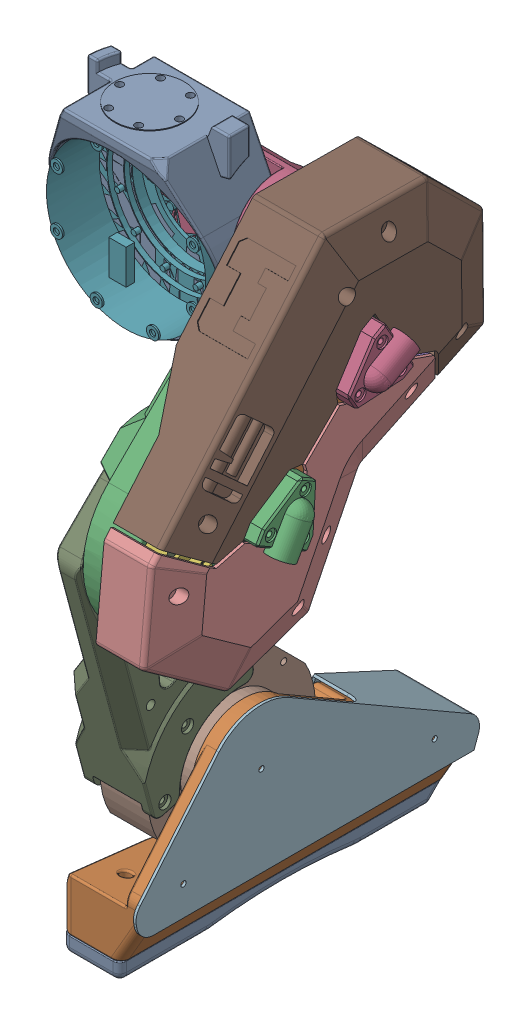
SolidWorks assembly 右腿, configuration 默认. Lengths in mm.
Overall size (184.93 459.26 275.12).
15 component instances, 12 part files, 44 mates.
Components (placement in the parent):
- 大腿right_yaw-1: 大腿right_yaw [默认] at (0 -55.5 53) size (99.54 110 58)
- 脚掌right_pitch-1: 脚掌right_pitch [默认] at (83.2 -422.4881 168.8962) x (0 -0.619688 -0.784849) z (-1 0 0) size (169.64 143.55 45)
- 大腿right_pitch-1: 大腿right_pitch [默认] at (63 -62.5711 79.7817) x (0 -0.707107 0.707107) z (-1 0 0) size (220 100.08 52.07)
- 大腿right_roll-1: 大腿right_roll [默认] at (63 -55.5 2) x (0 0 -1) z (1 0 0) size (71.94 70 103.87)
- A1电机模型-1: A1电机模型 [默认] at (107.05 -55.5 2) x (0 0.5 -0.866025) z (-1 0 0) size (92 92 49.05)
- A1电机模型-2: A1电机模型 [默认] at (107.05 -140.3528 86.8528) x (0 -0.866025 0.5) z (-1 0 0) size (92 92 49.05)
- A1电机模型-3: A1电机模型 [默认] at (0 -55.5 44.05) x (0 -1 0) z (0 0 -1) size (92 92 49.05)
- Go2电机模型-1: Go2电机模型 [默认] at (39.8 -275.5824 50.6181) x (0 0.707107 -0.707107) z (1 0 0) size (92.5 96.5 42.4)
- 小腿right_pitch-1: 小腿right_pitch [默认] at (73.5 -140.3528 86.8528) x (0 0.707107 -0.707107) z (1 0 0) size (144.22 133.76 40.34)
- 右大腿外壳-1: 右大腿外壳 [默认] at (70.05 -125.3028 488.7467) x (0 0.087156 -0.996195) z (1 0 0) size (207.48 194.95 50)
- 右脚鞋面壳-1: 右脚鞋面壳 [默认] at (83.2 -83.9006 -112.4365) x (0 0 -1) z (1 0 0) size (198.24 84 49)
- 鞋底脚板-1: 鞋底脚板 [默认] at (38.4265 -40.6299 -49.2728) x (0 -0.691677 -0.722207) z (1 0 0) size (136.26 135.6 33)
- 大腿左穿线板2-1: 大腿左穿线板2 [默认] at (108 -76.8035 65.5494) x (0 0.707107 -0.707107) z (1 0 0) size (105.13 45.22 9)
- 大腿波纹管连接件-2: 大腿波纹管连接件 [默认] at (117 -129.9252 80.9139) x (0 0.866025 -0.5) z (1 0 0) size (35 34 17.5)
- 大腿波纹管连接件-3: 大腿波纹管连接件 [默认] at (117 -61.4389 12.4276) x (0 -0.5 0.866025) z (1 0 0) size (35 34 17.5)
Mates (geometry in assembly coordinates):
- 重合1: coincident anti-aligned: plane of 大腿right_yaw-1 through (0 -55.5 10.5) normal (0 0 1); plane of A1电机模型-3 through (0 -55.5 10.5) normal (0 0 -1)
- 同心1: concentric aligned: cylinder of 大腿right_yaw-1 through (0 -55.5 0) axis (0 0 1) radius 46.5; cylinder of A1电机模型-3 through (0 -55.5 13.5) axis (0 0 1) radius 46
- 重合2: coincident aligned: plane of 大腿right_yaw-1 through (-5.5 0 25) normal (0 1 0)
- 重合3: coincident anti-aligned: plane of A1电机模型-3 through (0 -55.5 0) normal (0 0 -1)
- 对称1: symmetric aligned: plane of A1电机模型-3 through (-5 -55.5 49.05) normal (-1 0 0); plane of A1电机模型-3 through (5 -55.5 49.05) normal (1 0 0)
- 重合4: coincident anti-aligned: plane of 大腿right_roll-1 through (0 -55.5 0) normal (0 0 1); plane of A1电机模型-3 through (0 -55.5 0) normal (0 0 -1)
- 同心2: concentric: cylinder of 大腿right_yaw-1 through (0 -55.5 0) axis (0 0 1) radius 49; sphere of 大腿right_roll-1
- 同心3: concentric anti-aligned: cylinder of 大腿right_pitch-1 through (108 -55.5 2) axis (-1 0 0) radius 50; cylinder of A1电机模型-1 through (76.5 -55.5 2) axis (1 0 0) radius 46
- 重合5: coincident anti-aligned: plane of 大腿right_pitch-1 through (73.5 -55.5 2) normal (1 0 0); plane of A1电机模型-1 through (73.5 -55.5 2) normal (-1 0 0)
- 重合6: coincident aligned: plane of A1电机模型-1 through (63 -55.5 2) normal (-1 0 0); plane of A1电机模型-2 through (63 -140.3528 86.8528) normal (-1 0 0)
- 同心4: concentric anti-aligned: cylinder of 大腿right_pitch-1 through (108 -140.3528 86.8528) axis (-1 0 0) radius 50; cylinder of A1电机模型-2 through (76.5 -140.3528 86.8528) axis (1 0 0) radius 46
- 重合7: coincident anti-aligned: plane of A1电机模型-2 through (63 -140.3528 86.8528) normal (-1 0 0); plane of 小腿right_pitch-1 through (63 -140.3528 86.8528) normal (1 0 0)
- 同心5: concentric anti-aligned: cylinder of 大腿right_pitch-1 through (108 -140.3528 86.8528) axis (-1 0 0) radius 50; cylinder of 小腿right_pitch-1 through (33.5 -140.3528 86.8528) axis (1 0 0) radius 35
- 重合8: coincident anti-aligned: plane of 大腿right_roll-1 through (63 -55.5 2) normal (1 0 0); plane of A1电机模型-1 through (63 -55.5 2) normal (-1 0 0)
- 同心6: concentric anti-aligned: cylinder of 大腿right_pitch-1 through (108 -55.5 2) axis (-1 0 0) radius 50; cylinder of 大腿right_roll-1 through (62 -55.5 2) axis (1 0 0) radius 28
- 重合9: coincident anti-aligned: plane of Go2电机模型-1 through (67.5 -275.5824 50.6181) normal (1 0 0); plane of 小腿right_pitch-1 through (67.5 -275.5824 50.6181) normal (-1 0 0)
- 同心7: concentric anti-aligned: cylinder of Go2电机模型-1 through (67.5 -275.5824 50.6181) axis (-1 0 0) radius 48.25; cylinder of 小腿right_pitch-1 through (39.8 -275.5824 50.6181) axis (1 0 0) radius 50.5
- 同心8: concentric aligned: cylinder of Go2电机模型-1 through (44.8 -233.0824 50.6181) axis (-1 0 0) radius 1.75; cylinder of 小腿right_pitch-1 through (43.5 -233.0824 50.6181) axis (-1 0 0) radius 1.75
- 重合10: coincident anti-aligned: plane of 脚掌right_pitch-1 through (74.2 -422.4881 -89.4581) normal (-1 0 0); plane of Go2电机模型-1 through (74.2 -275.5824 50.6181) normal (1 0 0)
- 同心9: concentric anti-aligned: cylinder of 脚掌right_pitch-1 through (38.2 -275.5824 50.6181) axis (1 0 0) radius 30; cylinder of Go2电机模型-1 through (74.2 -275.5824 50.6181) axis (-1 0 0) radius 29.5
- 重合11: coincident anti-aligned: plane of 脚掌right_pitch-1 through (83.2 -422.4881 168.8962) normal (1 0 0); plane of 右脚鞋面壳-1 through (83.2 -275.5824 50.6181) normal (-1 0 0)
- 同心10: concentric aligned: cylinder of 脚掌right_pitch-1 through (38.2 -275.5824 50.6181) axis (1 0 0) radius 30; cylinder of 右脚鞋面壳-1 through (37.2 -275.5824 50.6181) axis (1 0 0) radius 32
- 同心11: concentric aligned: cylinder of 脚掌right_pitch-1 through (78.2 -310.5824 -49.3819) axis (1 0 0) radius 2.5; cylinder of 右脚鞋面壳-1 through (82.7 -310.5824 -49.3819) axis (1 0 0) radius 1.5
- 重合12: coincident anti-aligned: plane of 脚掌right_pitch-1 through (71.653 -345.5824 -89.4581) normal (0 -1 0); plane of 鞋底脚板-1 through (71.4265 -345.5824 119.1489) normal (0 1 0)
- 同心12: concentric aligned: cylinder of 脚掌right_pitch-1 through (54.9265 -285.5824 -38.8511) axis (0 -1 0) radius 1.55; cylinder of 鞋底脚板-1 through (54.9265 -251.1705 -38.8511) axis (0 -1 0) radius 1.55
- 同心13: concentric aligned: cylinder of 脚掌right_pitch-1 through (54.9265 -285.5824 99.1489) axis (0 -1 0) radius 1.55; cylinder of 鞋底脚板-1 through (54.9265 -251.1705 99.1489) axis (0 -1 0) radius 1.55
- 重合13: coincident anti-aligned: plane of 大腿right_pitch-1 through (108 -55.5 2) normal (1 0 0); plane of 大腿左穿线板2-1 through (108 -76.8035 65.5494) normal (-1 0 0)
- 同心14: concentric aligned: cylinder of A1电机模型-1 through (108.05 -61.0474 44.1364) axis (-1 0 0) radius 1.75; cylinder of 大腿左穿线板2-1 through (117 -61.0474 44.1364) axis (-1 0 0) radius 1.75
- 同心15: concentric aligned: cylinder of A1电机模型-1 through (108.05 -89.2175 27.8724) axis (-1 0 0) radius 1.75; cylinder of 大腿左穿线板2-1 through (117 -89.2175 27.8724) axis (-1 0 0) radius 1.75
- 同心17: concentric aligned: cylinder of A1电机模型-2 through (108.05 -114.4805 53.1353) axis (-1 0 0) radius 1.75; cylinder of 大腿左穿线板2-1 through (117 -114.4805 53.1353) axis (-1 0 0) radius 1.75
- 同心18: concentric aligned: cylinder of A1电机模型-2 through (108.05 -98.2164 81.3055) axis (-1 0 0) radius 1.75; cylinder of 大腿左穿线板2-1 through (117 -98.2164 81.3055) axis (-1 0 0) radius 1.75
- 重合14: coincident anti-aligned: plane of A1电机模型-2 through (108.05 -145.9002 44.7164) normal (1 0 0); plane of 右大腿外壳-1 through (108.05 -29.6276 35.7175) normal (-1 0 0)
- 同心19: concentric aligned: cylinder of A1电机模型-1 through (108.05 -13.3636 7.5474) axis (-1 0 0) radius 1.75; cylinder of 右大腿外壳-1 through (110.05 -13.3636 7.5474) axis (-1 0 0) radius 1.75
- 同心20: concentric aligned: cylinder of A1电机模型-1 through (108.05 -81.3724 -31.7175) axis (-1 0 0) radius 1.75; cylinder of 右大腿外壳-1 through (110.05 -81.3724 -31.7175) axis (-1 0 0) radius 1.75
- 同心21: concentric aligned: cylinder of 大腿左穿线板2-1 through (117 -74.9389 35.8103) axis (-1 0 0) radius 1.5; cylinder of 大腿波纹管连接件-3 through (127 -74.9389 35.8103) axis (-1 0 0) radius 1.5
- 重合15: coincident anti-aligned: plane of 大腿左穿线板2-1 through (117 -76.8035 65.5494) normal (1 0 0); plane of 大腿波纹管连接件-3 through (117 -61.4389 12.4276) normal (-1 0 0)
- 同心22: concentric aligned: cylinder of 大腿左穿线板2-1 through (117 -54.9126 23.1237) axis (-1 0 0) radius 1.5; cylinder of 大腿波纹管连接件-3 through (127 -54.9126 23.1237) axis (-1 0 0) radius 1.5
- 重合16: coincident aligned: plane of 大腿波纹管连接件-2 through (127 -129.9252 80.9139) normal (1 0 0); plane of 大腿波纹管连接件-3 through (127 -61.4389 12.4276) normal (1 0 0)
- 同心23: concentric aligned: cylinder of 大腿左穿线板2-1 through (117 -106.5425 67.4139) axis (-1 0 0) radius 1.5; cylinder of 大腿波纹管连接件-2 through (127 -106.5425 67.4139) axis (-1 0 0) radius 1.5
- 同心24: concentric aligned: cylinder of 大腿左穿线板2-1 through (117 -119.2291 87.4402) axis (-1 0 0) radius 1.5; cylinder of 大腿波纹管连接件-2 through (127 -119.2291 87.4402) axis (-1 0 0) radius 1.5
- 平行2: parallel: plane of 大腿right_yaw-1 through (-5.5 0 25) normal (0 1 0); line of 大腿right_roll-1 through (57.5 -21.2669 -5.0854) axis (-1 0 0)
- 平行3: parallel anti-aligned: plane of 大腿right_yaw-1 through (-5.5 0 25) normal (0 1 0); plane of 鞋底脚板-1 through (71.4265 -355.5824 -69.8511) normal (0 -1 0)
- 角度1: planar angle = 0.523599 rad anti-aligned: plane of 大腿right_roll-1 through (52 -50.5 34.1131) normal (0 1 0); plane of 大腿right_pitch-1 through (59 -19.2572 54.7744) normal (0 -0.866025 0.5)
- 角度2: planar angle = 0.785398 rad anti-aligned: plane of 大腿right_pitch-1 through (56 -104.9975 122.2082) normal (0 -1 0); plane of 小腿right_pitch-1 through (33.5 -115.6041 111.6016) normal (0 0.707107 0.707107)
